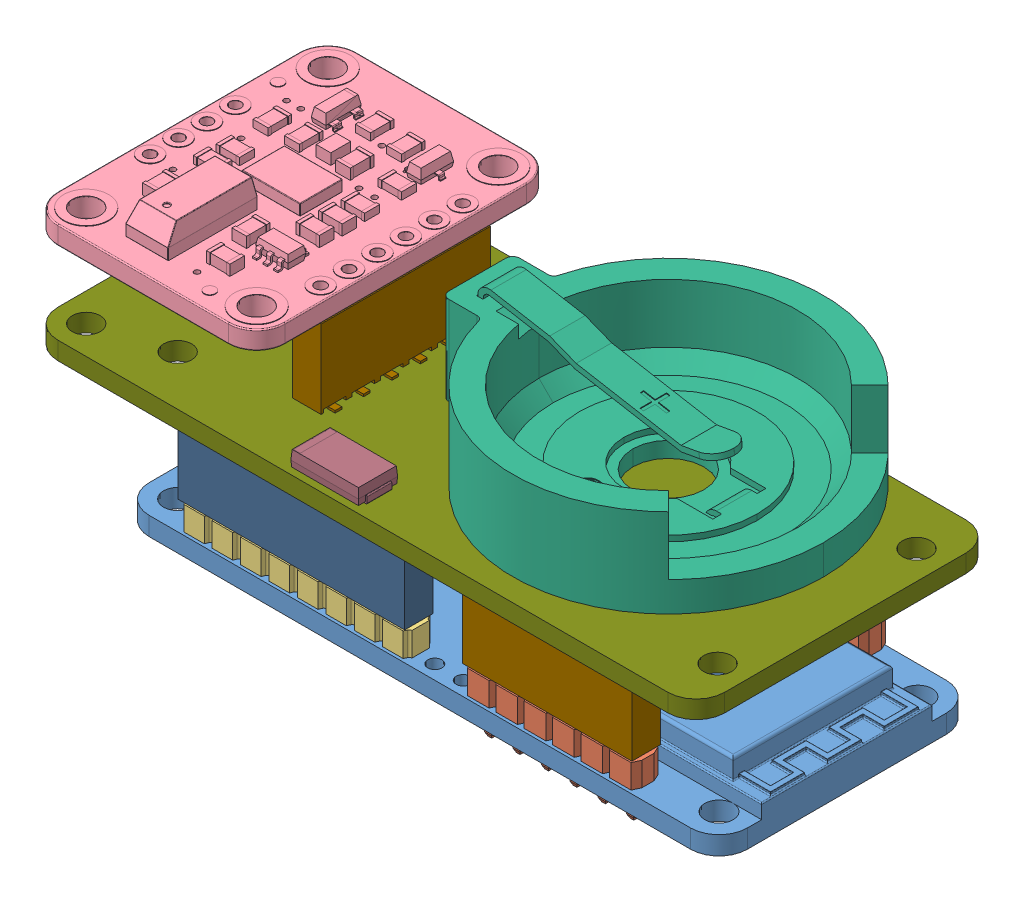
SolidWorks assembly RevC_Electrical_Assembly, configuration Default. Lengths in mm.
Overall size (59.74 25.93 27.76).
52 component instances, 16 part files, 18 mates.
Components (placement in the parent):
- Adafruit M0 AT1500 Feather_000-1: Adafruit M0 AT1500 Feather_000 [Default] at (11.6006 27.5935 45.6601) size (53.47 4.7 22.86)
- 68001-x06-1: 68001-x06 [Default] at (29.4441 29.4477 55.8201) x (-1 0 0) z (0 0 -1) size (15.24 11.43 2.41)
- 68001-x06-2: 68001-x06 [Default] at (1.5041 29.4477 35.5001) size (15.24 11.43 2.41)
- 68001-x06-3: 68001-x06 [Default] at (16.7441 29.4477 35.5001) size (15.24 11.43 2.41)
- p10129378-x08002blf-1: p10129378-x08002blf [Default] at (-8.6559 29.4445 55.8201) x (0 1 0) z (0 0 1) size (10.67 20.32 2.41)
- Adafruit_BNO055-1: Adafruit_BNO055 [Default] at (-1.0829 47.9345 58.9951) x (0 0 -1) z (1 0 0) size (26.67 4.2 20.32)
- p21014.step-2: p21014.step [Default] at (-188.6229 40.6345 105.8201) x (1 0 0) z (0 -1 0) size (59.61 27.76 20.34)
  - LED_0805_2012Metric.step-1: LED_0805_2012Metric.step [Default] at (194.24 -71.77 -0.05) x (1 0 0) z (0 0 -1) size (2 1.25 1.1)
    - SOLID.step-1: SOLID.step [Default] at origin size (2 1.25 1.1)
  - keystone-PN1027.step-1: keystone-PN1027.step [Default] at (211 -60.16 -2.55) x (0 1 0) z (-1 0 0) size (27.76 16.03 30.96)
    - SOLID-0.step-1: SOLID-0.step [Default] at origin size (27.76 16.03 30.96)
  - C_0603_1608Metric.step-1: C_0603_1608Metric.step [Default] at (203.265 -66.415 1.65) size (1.6 0.8 0.8)
    - SOLID-1.step-1: SOLID-1.step [Default] at origin size (1.6 0.8 0.8)
  - C_0603_1608Metric.step-2: C_0603_1608Metric.step [Default] at (203.365 -63.405 1.65) size (1.6 0.8 0.8)
    - SOLID-1.step-1: SOLID-1.step [Default] at origin size (1.6 0.8 0.8)
  - C_0603_1608Metric.step-3: C_0603_1608Metric.step [Default] at (199.255 -66.415 1.65) size (1.6 0.8 0.8)
    - SOLID-1.step-1: SOLID-1.step [Default] at origin size (1.6 0.8 0.8)
  - C_0603_1608Metric.step-4: C_0603_1608Metric.step [Default] at (199.355 -63.405 1.65) size (1.6 0.8 0.8)
    - SOLID-1.step-1: SOLID-1.step [Default] at origin size (1.6 0.8 0.8)
  - CP_EIA-3216-18_Kemet-A.step-1: CP_EIA-3216-18_Kemet-A.step [Default] at (196.02 -64.89 1.65) x (0 1 0) z (0 0 1) size (3.2 1.6 1.8)
    - SOLID-2.step-1: SOLID-2.step [Default] at origin size (3.2 1.6 1.8)
  - LED_0805_2012Metric.step-2: LED_0805_2012Metric.step [Default] at (190.84 -71.81 -0.05) x (0 1 0) z (0 0 -1) size (2 1.25 1.1)
    - SOLID.step-1: SOLID.step [Default] at origin size (2 1.25 1.1)
  - 91601-306LFc.step-1: 91601-306LFc.step [Default] at (186.27 -60.16 -7.25) x (0 -1 0) z (1 0 0) size (15.16 7.2 3.19)
    - SOLID-3.step-1: SOLID-3.step [Default] at origin size (15.16 7.2 3.19)
  - 91601-308LFc.step-1: 91601-308LFc.step [Default] at (188.73 -50 8.85) x (1 0 0) z (0 -1 0) size (20.24 7.2 3.19)
    - SOLID-4.step-1: SOLID-4.step [Default] at origin size (20.24 7.2 3.19)
  - 91601-412ALFc.step-1: 91601-412ALFc.step [Default] at (203.97 -70.32 8.85) x (1 0 0) z (0 -1 0) size (30.4 7.2 3.19)
    - SOLID-5.step-1: SOLID-5.step [Default] at origin size (30.4 7.2 3.19)
  - 91601-306LFc.step-2: 91601-306LFc.step [Default] at (211.59 -50 8.85) x (1 0 0) z (0 -1 0) size (15.16 7.2 3.19)
    - SOLID-3.step-1: SOLID-3.step [Default] at origin size (15.16 7.2 3.19)
  - R_0603_1608Metric.step-1: R_0603_1608Metric.step [Default] at (198.265 -58.125 1.65) x (0 1 0) z (0 0 1) size (1.6 0.8 0.45)
    - SOLID-6.step-1: SOLID-6.step [Default] at origin size (1.6 0.8 0.45)
  - R_0603_1608Metric.step-2: R_0603_1608Metric.step [Default] at (195.165 -54.115 1.65) x (0 1 0) z (0 0 1) size (1.6 0.8 0.45)
    - SOLID-6.step-1: SOLID-6.step [Default] at origin size (1.6 0.8 0.45)
  - R_0603_1608Metric.step-3: R_0603_1608Metric.step [Default] at (204.21 -54.11 1.65) x (0 1 0) z (0 0 1) size (1.6 0.8 0.45)
    - SOLID-6.step-1: SOLID-6.step [Default] at origin size (1.6 0.8 0.45)
  - R_0603_1608Metric.step-4: R_0603_1608Metric.step [Default] at (201.27 -58.12 1.65) x (0 1 0) z (0 0 1) size (1.6 0.8 0.45)
    - SOLID-6.step-1: SOLID-6.step [Default] at origin size (1.6 0.8 0.45)
  - R_0603_1608Metric.step-5: R_0603_1608Metric.step [Default] at (201.27 -54.09 1.65) x (0 1 0) z (0 0 1) size (1.6 0.8 0.45)
    - SOLID-6.step-1: SOLID-6.step [Default] at origin size (1.6 0.8 0.45)
  - R_0603_1608Metric.step-6: R_0603_1608Metric.step [Default] at (198.265 -54.115 1.65) x (0 1 0) z (0 0 1) size (1.6 0.8 0.45)
    - SOLID-6.step-1: SOLID-6.step [Default] at origin size (1.6 0.8 0.45)
  - R_0603_1608Metric.step-7: R_0603_1608Metric.step [Default] at (204.21 -58.135 1.65) x (0 1 0) z (0 0 1) size (1.6 0.8 0.45)
    - SOLID-6.step-1: SOLID-6.step [Default] at origin size (1.6 0.8 0.45)
  - CP_EIA-6032-15_Kemet-U.step-1: CP_EIA-6032-15_Kemet-U.step [Default] at (193.21 -48.98 -0.05) x (1 0 0) z (0 0 -1) size (6.3 3.5 1.5)
    - SOLID-7.step-1: SOLID-7.step [Default] at origin size (6.3 3.5 1.5)
  - SOT-1333-1.step-1: SOT-1333-1.step [Default] at (193.96 -48.98 -0.05) x (0 1 0) z (0 0 -1) size (2.48 2 0.52)
    - SOLID-8.step-1: SOLID-8.step [Default] at origin size (2.48 2 0.52)
  - SOT-223.step-1: SOT-223.step [Default] at (208.64 -60.08 1.65) x (0 1 0) z (0 0 1) size (7 6.5 1.7)
    - SOLID-9.step-1: SOLID-9.step [Default] at origin size (7 6.5 1.7)
  - COMPOUND.step-1: COMPOUND.step [Default] at origin size (59.61 26.67 1.6)
Mates (geometry in assembly coordinates):
- Width3: width aligned: plane of p10129378-x08002blf-1 through (-8.6559 28.414 56.1401) normal (0 0 1); plane of p10129378-x08002blf-1 through (-8.6559 28.414 55.5001) normal (0 0 -1)
- Width5: width aligned: plane of 68001-x06-3 through (29.4441 31.9115 35.1826) normal (0 0 -1); plane of 68001-x06-3 through (29.4441 31.9115 35.8176) normal (0 0 1)
- Width6: width aligned: plane of 68001-x06-2 through (1.5041 31.9115 35.1826) normal (0 0 -1); plane of 68001-x06-2 through (1.5041 31.9115 35.8176) normal (0 0 1)
- Width7: width aligned: plane of 68001-x06-3 through (29.7616 31.9115 35.5001) normal (1 0 0); plane of 68001-x06-3 through (29.1266 31.9115 35.5001) normal (-1 0 0)
- Width8: width anti-aligned: plane of 68001-x06-2 through (14.5216 31.9115 35.5001) normal (1 0 0); plane of 68001-x06-2 through (13.8866 31.9115 35.5001) normal (-1 0 0)
- Width9: width aligned: plane of p10129378-x08002blf-1 through (-8.3359 28.414 55.8201) normal (1 0 0); plane of p10129378-x08002blf-1 through (-8.9759 28.414 55.8201) normal (-1 0 0)
- Width10: width anti-aligned: plane of 68001-x06-1 through (29.4441 31.9115 55.5026) normal (0 0 -1); plane of 68001-x06-1 through (29.4441 31.9115 56.1376) normal (0 0 1)
- Width11: width anti-aligned: plane of 68001-x06-1 through (29.7616 31.9115 55.8201) normal (1 0 0); plane of 68001-x06-1 through (29.1266 31.9115 55.8201) normal (-1 0 0)
- Coincident6: coincident anti-aligned: plane of Adafruit M0 AT1500 Feather_000-1 through (35.7941 29.2445 54.5501) normal (0 1 0); plane of 68001-x06-1 through (17.4045 29.2445 56.3789) normal (0 -1 0)
- Coincident7: coincident anti-aligned: plane of Adafruit M0 AT1500 Feather_000-1 through (35.7941 29.2445 54.5501) normal (0 1 0); plane of 68001-x06-2 through (5.9237 29.2445 34.9413) normal (0 -1 0)
- Coincident8: coincident anti-aligned: plane of Adafruit M0 AT1500 Feather_000-1 through (35.7941 29.2445 54.5501) normal (0 1 0); plane of 68001-x06-3 through (23.7037 29.2445 34.9413) normal (0 -1 0)
- Coincident9: coincident anti-aligned: plane of Adafruit M0 AT1500 Feather_000-1 through (35.7941 29.2445 54.5501) normal (0 1 0); plane of p10129378-x08002blf-1 through (-9.3159 29.2445 56.3801) normal (0 -1 0)
- Concentric7: concentric: cylinder of assembly; cylinder of assembly; cylinder of Adafruit M0 AT1500 Feather_000-1 through (-12.5929 29.2445 36.7701) axis (0 -1 0) radius 1.27; cylinder of p21014.step-2/COMPOUND.step-1 through (-12.5929 41.4345 36.7701) axis (0 -1 0) radius 1.25; cylinder of assembly; cylinder of assembly; cylinder of Adafruit M0 AT1500 Feather_000-1; cylinder of ?; plane of assembly; plane of assembly; plane of ?; plane of p21014.step-2/91601-412ALFc.step-1/SOLID-5.step-1; cylinder of assembly; cylinder of assembly; cylinder of Adafruit_BNO055-1; cylinder of ?; cylinder of assembly; cylinder of assembly; cylinder of ?; cylinder of ?; plane of assembly; plane of assembly; plane of ?; plane of p21014.step-2/91601-306LFc.step-1/SOLID-3.step-1
- Concentric8: concentric: cylinder of Adafruit M0 AT1500 Feather_000-1 through (-12.5929 29.2445 54.5501) axis (0 -1 0) radius 1.27; cylinder of p21014.step-2/COMPOUND.step-1 through (-12.5929 41.4345 54.5501) axis (0 -1 0) radius 1.25
- Coincident12: coincident anti-aligned: plane of 68001-x06-2 through (5.9237 31.7845 34.9413) normal (0 1 0); plane of p21014.step-2/91601-412ALFc.step-1/SOLID-5.step-1 through (15.3471 31.7845 35.5001) normal (0 -1 0)
- Concentric9: concentric: cylinder of Adafruit_BNO055-1 through (-18.8629 49.5845 34.8651) axis (0 -1 0) radius 1.25; cylinder of p21014.step-2/COMPOUND.step-1 through (-18.8629 41.4345 34.8651) axis (0 -1 0) radius 1.25
- Concentric10: concentric: cylinder of Adafruit_BNO055-1 through (-18.8629 49.5845 56.4551) axis (0 -1 0) radius 1.25; cylinder of p21014.step-2/COMPOUND.step-1 through (-18.8629 41.4345 56.4551) axis (0 -1 0) radius 1.25
- Coincident13: coincident anti-aligned: plane of Adafruit_BNO055-1 through (-2.3529 47.8845 52.0101) normal (0 -1 0); plane of p21014.step-2/91601-306LFc.step-1/SOLID-3.step-1 through (-2.3529 47.8845 45.6601) normal (0 1 0)
